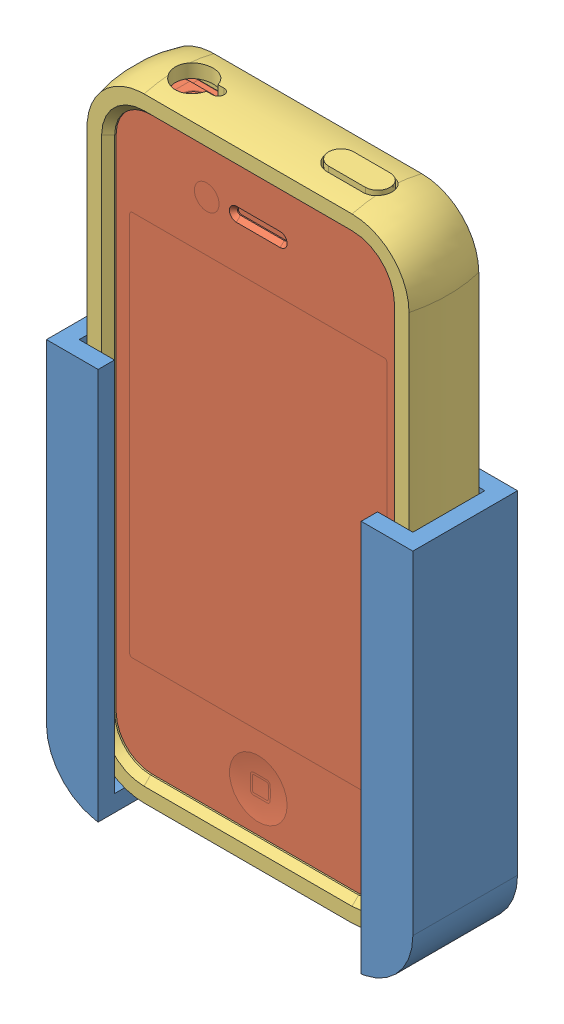
SolidWorks assembly Assembly, configuration Default. Lengths in mm.
Overall size (71.12 124.79 20.32).
3 component instances, 3 part files, 6 mates.
Components (placement in the parent):
- holster-1: holster [Default] at (132.9404 -43.4742 38.3722) size (71.12 76.2 20.32)
- iPhone_4-1: iPhone_4 [iPhone_4S] at (168.8926 19.8342 38.6988) size (59.15 115.75 9.34)
- Speck-1: Speck [Default] at (168.4623 20.2925 38.1563) x (-1 0 0) z (0 1 0) size (64.85 13.54 121.5)
Mates (geometry in assembly coordinates):
- Coincident9: coincident anti-aligned: plane of iPhone_4-1 through (189.6676 68.9092 34.0288) normal (0 0 -1); plane of Speck-1 through (190.4472 -28.2533 34.0288) normal (0 0 1)
- Coincident16: coincident anti-aligned: plane of iPhone_4-1 through (148.1176 78.0092 41.7838) normal (0 1 0); plane of Speck-1 through (186.8646 78.0092 38.1563) normal (0 -1 0)
- Distance2: distance = 0.254 mm aligned: plane of iPhone_4-1 through (198.1676 -29.2408 41.7838) normal (1 0 0); cylinder of Speck-1 through (173.2049 -28.2533 38.1563) axis (0 1 0) radius 24.7087
- Distance1: distance = 0.254 mm anti-aligned: plane of holster-1 through (136.1154 -109.7337 45.3572) normal (1 0 0); cylinder of Speck-1 through (163.7197 -28.2533 38.1563) axis (0 1 0) radius 27.3503
- Coincident17: coincident anti-aligned: plane of holster-1 through (136.1154 -109.7337 31.3872) normal (0 0 1); plane of Speck-1 through (190.4472 -28.2533 31.3872) normal (0 0 -1)
- Tangent5: tangent: line of holster-1 through (142.9734 -40.1595 39.7692) axis (0 0 1); cylinder of Speck-1 through (188.649 -12.8092 38.1563) axis (-1 0 0) radius 27.3503
